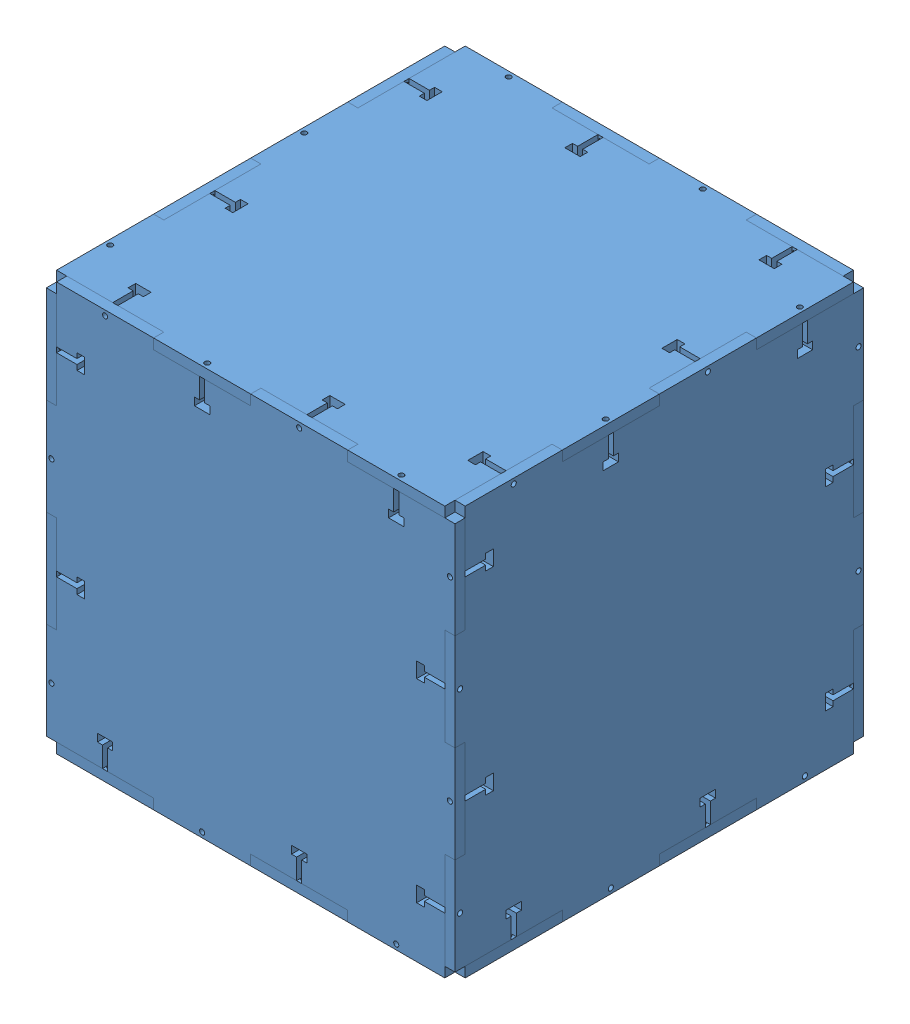
SolidWorks assembly Panel Assembly, configuration Default. Lengths in mm.
Overall size (127 127 127).
6 component instances, 1 part files, 26 mates.
Components (placement in the parent):
- Panel 2-1: Panel 2 [Default] at origin size (127 127 3.17)
- Panel 2-2: Panel 2 [Default] at (60.325 0 -60.325) x (0 0 -1) z (1 0 0) size (127 127 3.17)
- Panel 2-3: Panel 2 [Default] at (0 0 -120.65) x (-1 0 0) z (0 0 -1) size (127 127 3.17)
- Panel 2-4: Panel 2 [Default] at (-60.325 0 -60.325) x (0 0 1) z (-1 0 0) size (127 127 3.17)
- Panel 2-5: Panel 2 [Default] at (0 60.325 -60.325) x (1 0 0) z (0 1 0) size (127 127 3.17)
- Panel 2-6: Panel 2 [Default] at (0 -60.325 -60.325) x (1 0 0) z (0 -1 0) size (127 127 3.17)
Mates (geometry in assembly coordinates):
- Coincident3: coordinate: point of Panel-1
- Coincident4: coincident: plane of Panel-1 through (0 0 0) normal (-1 0 0); plane of Panel-2 through (0 19.05 63.5) normal (1 0 0)
- Coincident5: coincident: plane of Panel-1 through (3.175 63.5 60.325) normal (0 0 1); plane of Panel-2 through (-60.325 0 60.325) normal (0 0 -1)
- Coincident6: coincident anti-aligned: plane of Panel-1 through (3.175 19.05 63.5) normal (0 1 0); plane of Panel-2 through (3.175 19.05 63.5) normal (0 -1 0)
- Coincident7: coincident: plane of Panel-2 through (-123.825 -19.05 63.5) normal (0 1 0); plane of Panel-3 through (-120.65 -19.05 63.5) normal (0 -1 0)
- Coincident8: coincident: plane of Panel-2 through (-120.65 19.05 63.5) normal (-1 0 0); plane of Panel-3 through (-120.65 0 0) normal (1 0 0)
- Coincident9: coincident anti-aligned: plane of Panel-2 through (-60.325 0 60.325) normal (0 0 -1); plane of Panel-3 through (-120.65 63.5 60.325) normal (0 0 1)
- Coincident10: coincident: plane of Panel-3 through (-120.65 0 0) normal (1 0 0); plane of Panel-4 through (-120.65 -19.05 -60.325) normal (-1 0 0)
- Coincident11: coincident: plane of Panel-3 through (-120.65 63.5 -60.325) normal (0 0 -1); plane of Panel-4 through (-60.325 0 -60.325) normal (0 0 1)
- Coincident12: coincident anti-aligned: plane of Panel-3 through (-120.65 19.05 -63.5) normal (0 1 0); plane of Panel-4 through (-123.825 19.05 -60.325) normal (0 -1 0)
- Coincident13: coordinate: unknown of Panel 2-1
- Coincident14: coincident anti-aligned: plane of Panel 2-1 through (0 0 0) normal (0 0 -1); plane of Panel 2-2 through (63.5 30.1625 0) normal (0 0 1)
- Coincident15: coincident anti-aligned: plane of Panel 2-1 through (60.325 30.1625 3.175) normal (1 0 0); plane of Panel 2-2 through (60.325 0 -60.325) normal (-1 0 0)
- Coincident16: coincident anti-aligned: plane of Panel 2-1 through (63.5 30.1625 3.175) normal (0 -1 0); plane of Panel 2-2 through (63.5 30.1625 3.175) normal (0 1 0)
- Coincident17: coincident anti-aligned: plane of Panel 2-2 through (63.5 30.1625 -120.65) normal (0 0 -1); plane of Panel 2-3 through (0 0 -120.65) normal (0 0 1)
- Coincident18: coincident anti-aligned: plane of Panel 2-2 through (60.325 0 -60.325) normal (-1 0 0); plane of Panel 2-3 through (60.325 30.1625 -123.825) normal (1 0 0)
- Coincident19: coincident anti-aligned: plane of Panel 2-2 through (63.5 30.1625 -123.825) normal (0 -1 0); plane of Panel 2-3 through (63.5 30.1625 -123.825) normal (0 1 0)
- Coincident20: coincident anti-aligned: plane of Panel 2-3 through (-60.325 30.1625 -123.825) normal (-1 0 0); plane of Panel 2-4 through (-60.325 0 -60.325) normal (1 0 0)
- Coincident21: coincident anti-aligned: plane of Panel 2-3 through (0 0 -120.65) normal (0 0 1); plane of Panel 2-4 through (-63.5 30.1625 -120.65) normal (0 0 -1)
- Coincident22: coincident anti-aligned: plane of Panel 2-3 through (-63.5 30.1625 -123.825) normal (0 -1 0); plane of Panel 2-4 through (-63.5 30.1625 -123.825) normal (0 1 0)
- Coincident23: coincident anti-aligned: plane of Panel 2-2 through (63.5 60.325 -120.65) normal (0 1 0); plane of Panel 2-5 through (0 60.325 -60.325) normal (0 -1 0)
- Coincident24: coincident anti-aligned: plane of Panel 2-2 through (60.325 0 -60.325) normal (-1 0 0); plane of Panel 2-5 through (60.325 63.5 -90.4875) normal (1 0 0)
- Coincident25: coincident anti-aligned: plane of Panel 2-3 through (0 0 -120.65) normal (0 0 1); plane of Panel 2-5 through (60.325 63.5 -120.65) normal (0 0 -1)
- Coincident26: coincident anti-aligned: plane of Panel 2-1 through (-60.325 -60.325 3.175) normal (0 -1 0); plane of Panel 2-6 through (0 -60.325 -60.325) normal (0 1 0)
- Coincident27: coincident anti-aligned: plane of Panel 2-1 through (-30.1625 -63.5 3.175) normal (-1 0 0); plane of Panel 2-6 through (-30.1625 -63.5 3.175) normal (1 0 0)
- Coincident28: coincident anti-aligned: plane of Panel 2-1 through (0 0 0) normal (0 0 -1); plane of Panel 2-6 through (-30.1625 -63.5 0) normal (0 0 1)
